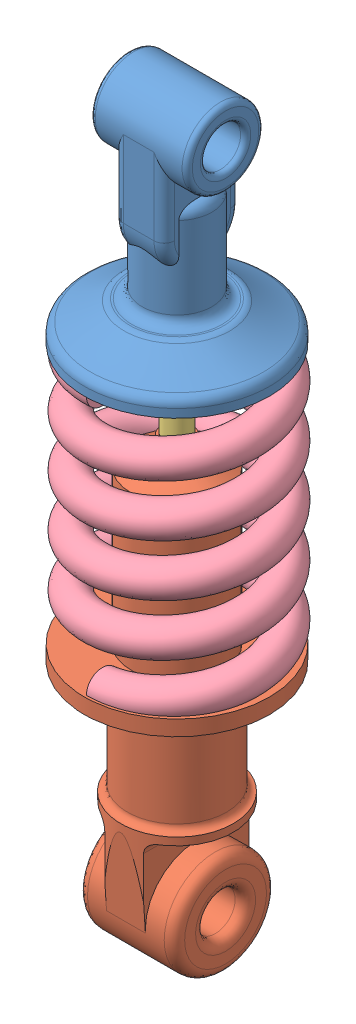
SolidWorks assembly Shock, configuration Default. Lengths in mm.
Overall size (46.33 187.22 47.49).
4 component instances, 4 part files, 12 mates.
Components (placement in the parent):
- Shock Anchor_11-1: Shock Anchor_11 [Default] at (152.5977 0 0) size (46 57.15 46)
- Shock Tube 1_11-1: Shock Tube 1_11 [Default] at (152.5977 -145.95 0) x (-1 0 0) z (0 0 1) size (46 110.41 46)
- Shock Absorber Rod_11-1: Shock Absorber Rod_11 [Default] at (152.5977 -66.839 0) x (0.425717 0 0.904857) z (-0.904857 0 0.425717) size (6.35 19.21 6.35)
- Shock Spring_11-1: Shock Spring_11 [Default] at (152.9274 -111.8466 -0.1604) size (46 72.22 47.49)
Mates (geometry in assembly coordinates):
- Concentric1: concentric: cylinder of Shock Anchor_11-1 through (158.9477 0 0) axis (-1 0 0) radius 5
- Coincident2: coincident aligned: plane of Shock Anchor_11-1 through (152.5977 0 0) normal (0 1 0)
- Coincident3: coincident aligned: plane of Shock Anchor_11-1 through (152.5977 0 0) normal (0 0 1)
- Concentric2: concentric aligned: circle of Shock Anchor_11-1; circle of Shock Absorber Rod_11-1
- Coincident4: coincident anti-aligned: plane of Shock Anchor_11-1 through (152.5977 -47.625 0) normal (0 -1 0); plane of Shock Absorber Rod_11-1 through (152.5977 -47.625 0) normal (0 1 0)
- Concentric3: concentric anti-aligned: cylinder of Shock Tube 1_11-1 through (152.5977 -92.6874 0) axis (0 1 0) radius 3.175; cylinder of Shock Absorber Rod_11-1 through (152.5977 -47.625 0) axis (0 -1 0) radius 3.175
- Coincident5: coincident anti-aligned: plane of Shock Anchor_11-1 through (152.5977 -47.625 0) normal (0 -1 0); plane of Shock Spring_11-1 through (152.9274 -47.625 -0.1604) normal (0 1 0)
- Lock1: lock: unknown of Shock Anchor_11-1; unknown of Shock Spring_11-1
- Parallel1: parallel anti-aligned: cylinder of Shock Anchor_11-1 through (158.9477 0 0) axis (-1 0 0) radius 5; cylinder of Shock Tube 1_11-1 through (140.5327 -165 0) axis (1 0 0) radius 4.9166
- Parallel4: parallel anti-aligned: line of Shock Anchor_11-1 through (0 24.13 164.6627) axis (0 0 -1); line of Shock Tube 1_11-1 through (24.13 140.5327 -165) axis (0 1 0)
- LimitDistance1: limit distance = 165 mm: line of Shock Tube 1_11-1 through (24.13 140.5327 -165) axis (0 1 0); line of Shock Anchor_11-1 through (0 24.13 164.6627) axis (0 0 -1)
- Distance1: distance = 165 mm: line of Shock Anchor_11-1 through (0 24.13 164.6627) axis (0 0 -1); line of Shock Tube 1_11-1 through (24.13 140.5327 -165) axis (0 1 0)
